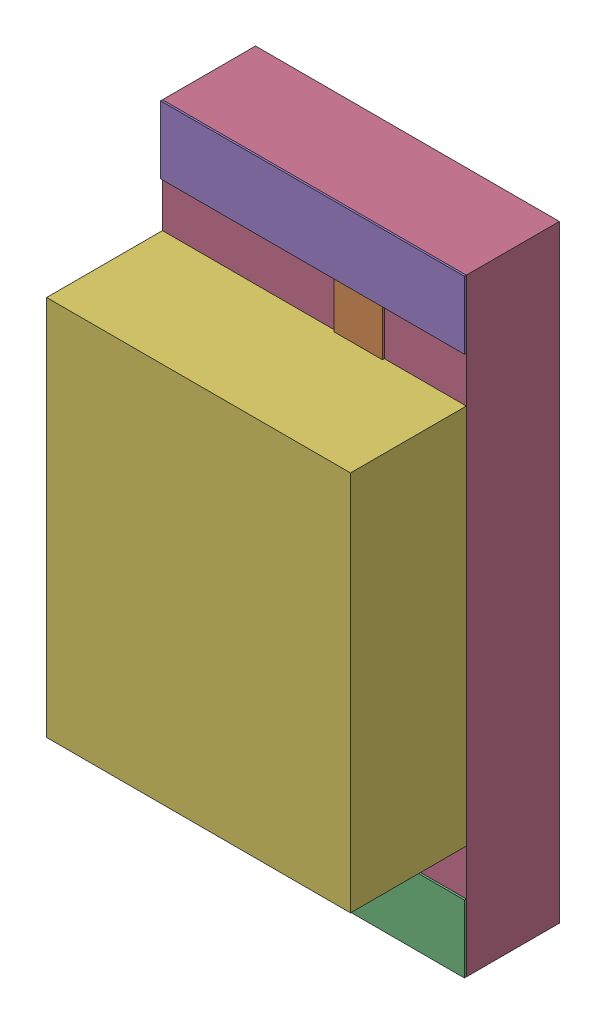
SolidWorks assembly D1, configuration Défaut. Lengths in mm.
Overall size (1.6 3.2 1.52).
15 component instances, 6 part files, 0 mates.
Components (placement in the parent):
- SW3dPS-LED1206G-1: SW3dPS-LED1206G [Défaut] at (35.6997 71.852 0) x (0 1 0) z (0 0 1) size (3.2 1.6 1.52)
  - SW3dPS-LED1206G_Open_CASCADE_STEP_translator_6.2_262.2-1: SW3dPS-LED1206G_Open_CASCADE_STEP_translator_6.2_262.2 [Défaut] at origin size (3.2 1.6 1.1)
    - SW3dPS-LED1206G_352699472-1: SW3dPS-LED1206G_352699472 [Défaut] at (0.6096 0.0254 0.5027) size (0.65 0.76 0.01)
      - SW3dPS-LED1206G_Extruded-1: SW3dPS-LED1206G_Extruded [Défaut] at origin size (0.65 0.76 0.01)
    - SW3dPS-LED1206G_352698192-1: SW3dPS-LED1206G_352698192 [Défaut] at (2.1971 0.0254 0.5027) size (1.14 0.76 0.01)
      - SW3dPS-LED1206G_Extruded4-1: SW3dPS-LED1206G_Extruded4 [Défaut] at origin size (1.14 0.76 0.01)
    - SW3dPS-LED1206G_352697808-1: SW3dPS-LED1206G_352697808 [Défaut] at (0.1016 0.0127 0.5027) size (0.36 1.6 0.01)
      - SW3dPS-LED1206G_Extruded2-1: SW3dPS-LED1206G_Extruded2 [Défaut] at origin size (0.36 1.6 0.01)
    - SW3dPS-LED1206G_352697936-1: SW3dPS-LED1206G_352697936 [Défaut] at (1.524 0.0127 0.0127) size (3.2 1.6 0.49)
      - SW3dPS-LED1206G_Extruded1-1: SW3dPS-LED1206G_Extruded1 [Défaut] at origin size (3.2 1.6 0.49)
    - SW3dPS-LED1206G_352697808-2: SW3dPS-LED1206G_352697808 [Défaut] at (2.9464 0.0127 0.5027) size (0.36 1.6 0.01)
      - SW3dPS-LED1206G_Extruded2-1: SW3dPS-LED1206G_Extruded2 [Défaut] at origin size (0.36 1.6 0.01)
    - SW3dPS-LED1206G_352700880-1: SW3dPS-LED1206G_352700880 [Défaut] at (1.524 0.0127 0.5027) size (2.01 1.6 0.61)
      - SW3dPS-LED1206G_Extruded3-1: SW3dPS-LED1206G_Extruded3 [Défaut] at origin size (2.01 1.6 0.61)
  - SW3dPS-LED1206G_Board-1: SW3dPS-LED1206G_Board [Défaut] at (0 0 -0.4039) size (0.03 0.03 0.42)
